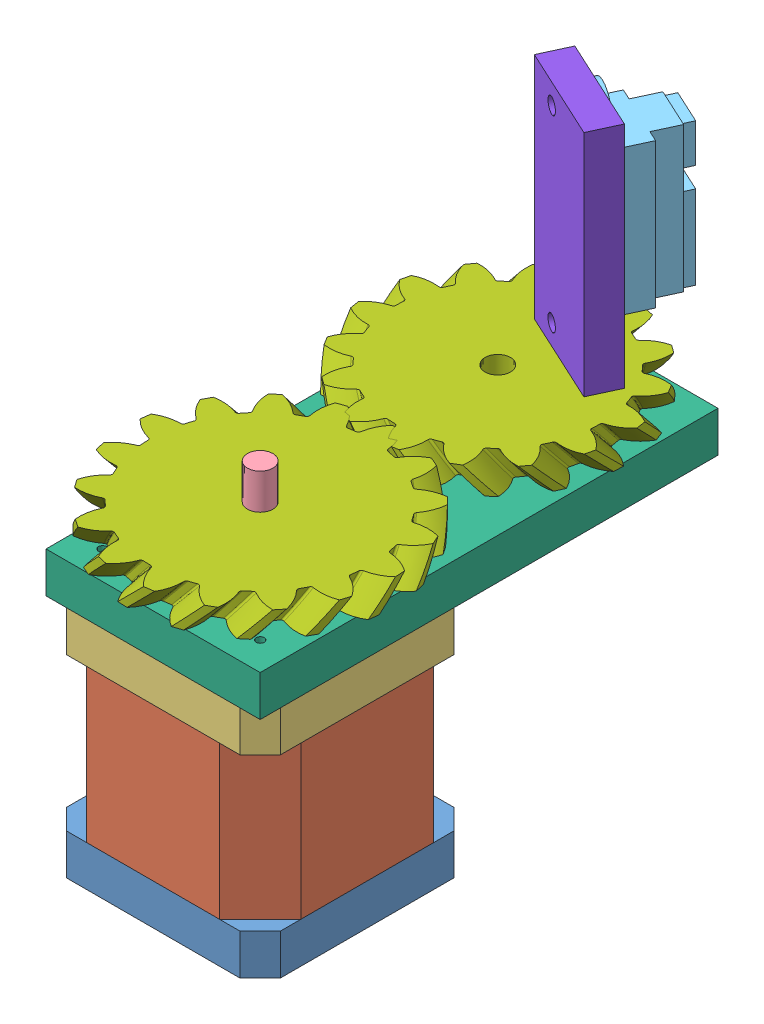
SolidWorks assembly lidar-assembly, configuration Default. Lengths in mm.
Overall size (58.66 107 107.78).
10 component instances, 8 part files, 15 mates.
Components (placement in the parent):
- motor-1: motor [Default] at origin size (42.1 69 42.1)
  - bottom plate-1: bottom plate [Default] at origin size (42.1 8 42.1)
  - motor-boddy-2: motor-boddy [Default] at (0 8 0) size (42.1 30 42.1)
  - motor-top-1: motor-top [Default] at (0 38 0) size (42.1 10 42.1)
  - Part4^motor-1: Part4^motor [Default] at (0 46 0) x (1 0 0) z (0 1 0) size (5 5 23) (virtual)
- sensor-1: sensor [Default] at (4.661 83.9 -60.6135) x (0 1 0) z (-0.907369 0 -0.420336) size (43.3 14 18.8)
- plate-1: plate [Default] at (0 46 0) x (1 0 0) z (0 1 0) size (42.1 90 8)
- helical gear_4_iso-2: helical gear_4_iso [ISO - RH Helical gear 2M 17T 45HA 20PA 5FW ---17A75H50L5.0N] at (0 57 0) x (0 1 0) z (-0.133657 0 0.991028) size (5 52.16 52.16)
- helical gear_4_iso-5: helical gear_4_iso [ISO - LH Helical gear 2M 16T 45HA 20PA 5FW ---16A75H50L5.0N] at (0 57 -46.7079) x (0 1 0) z (0.986915 0 -0.161239) size (5 49.28 49.28)
- holder-1: holder [Default] at (10.9924 84.5 -43.3534) x (-0.420336 0 0.907369) z (-0.907369 0 -0.420336) size (6 45 20)
Mates (geometry in assembly coordinates):
- InPlace1: in place: plane of motor-1/motor-top-1 through (0 46 0) normal (0 1 0); plane of ? through (0 46 0) normal (0 1 0); moOrthogonalPlaneRef_w of motor-1/motor-top-1 through (0 46 0) normal (0 1 0); plane of ? through (0 46 0) normal (0 0 -1); plane of motor-1/motor-top-1 through (0 46 0) normal (0 1 0); plane of ? through (0 46 0) normal (1 0 0); plane of motor-1/motor-top-1 through (0 46 0) normal (0 1 0); unknown of ?
- Coincident1: coincident aligned: plane of motor-1/motor-top-1; plane of plate-1
- Coincident2: coincident aligned: moOrthogonalPlaneRef_w of motor-1/motor-top-1 through (0 46 0) normal (0 0 -1); plane of plate-1 through (0 46 0) normal (0 0 -1)
- Coincident3: coincident anti-aligned: moOrthogonalPlaneRef_w of motor-1/motor-top-1 through (0 46 0) normal (-1 0 0); plane of plate-1 through (0 46 0) normal (1 0 0)
- Distance2: distance = 3 mm anti-aligned: plane of helical gear_4_iso-2 through (0 57 0) normal (0 -1 0); plane of plate-1 through (0 54 0) normal (0 1 0)
- Concentric1: concentric aligned: cylinder of motor-1/Part4^motor-1 through (0 69 0) axis (0 -1 0) radius 2.5; cylinder of helical gear_4_iso-2 through (0 119.5 0) axis (0 -1 0) radius 2.5
- Distance7: distance = 3 mm anti-aligned: plane of helical gear_4_iso-5 through (0 57 -46.7079) normal (0 -1 0); plane of plate-1 through (0 54 0) normal (0 1 0)
- Coincident15: coincident: point of helical gear_4_iso-5; plane of assembly
- Coincident20: coincident anti-aligned: plane of sensor-1 through (4.661 83.9 -60.6135) normal (-0.420336 0 0.907369); plane of holder-1 through (-1.6906 107 -63.5559) normal (0.420336 0 -0.907369)
- Concentric3: concentric anti-aligned: cylinder of sensor-1 through (5.2915 66 -61.9746) axis (-0.420336 0 0.907369) radius 1.5; cylinder of holder-1 through (2.139 66 -55.1693) axis (0.420336 0 -0.907369) radius 1.5
- Parallel1: parallel anti-aligned: cylinder of sensor-1 through (5.2915 101.8 -61.9746) axis (-0.420336 0 0.907369) radius 1.5; cylinder of holder-1 through (2.139 103 -55.1693) axis (0.420336 0 -0.907369) radius 1.5
- Parallel2: parallel aligned: plane of sensor-1 through (1.7054 69.65 -69.6973) normal (-0.907369 0 -0.420336); plane of holder-1 through (-7.155 84.5 -51.7601) normal (-0.907369 0 -0.420336)
- Concentric5: concentric anti-aligned: cylinder of plate-1 through (0 46 -46.7079) axis (0 1 0) radius 2.5; cylinder of helical gear_4_iso-5 through (0 119.5 -46.7079) axis (0 -1 0) radius 2.5
- Coincident21: coincident anti-aligned: plane of helical gear_4_iso-5 through (0 62 -46.7079) normal (0 1 0); plane of holder-1 through (-1.6906 62 -63.5559) normal (0 -1 0)
- Parallel3: parallel aligned: line of holder-1 through (-4.2126 62 -58.1117) axis (0.907369 0 0.420336); line of assembly
